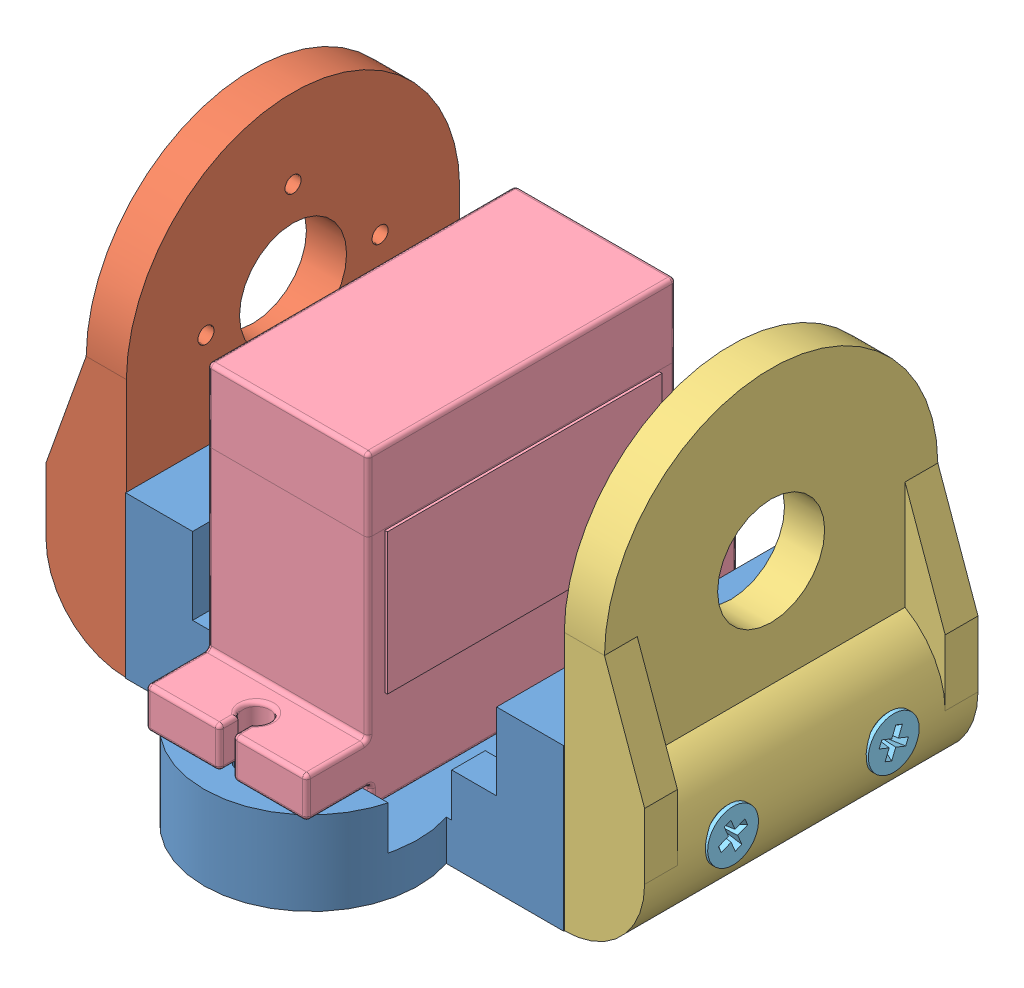
SolidWorks assembly Ensamblaje-Eslabon5, configuration Predeterminado. Lengths in mm.
Overall size (45.34 36.4 35.5).
8 component instances, 5 part files, 15 mates.
Components (placement in the parent):
- Eslabon5A-Servo-1: Eslabon5A-Servo [Predeterminado] at origin size (32.7 12 35.5)
- Eslabon5B-1: Eslabon5B [Predeterminado] at (-16.1231 15.0816 -5.7351) x (0 1 0) z (0 0 1) size (31.65 6 24.89)
- Eslabon5C-1: Eslabon5C [Predeterminado] at (16.5769 15.0816 -4.9919) x (0 1 0) z (0 0 -1) size (31.65 6 24.89)
- MG90S-Servo-1: MG90S-Servo [Default] at (0.2252 27.75 -0.1146) x (0 0 -1) z (-1 0 0) size (32.2 32.5 12.4)
- flat head screw_am-1: flat head screw_am [B18.6.7M - M2 x 0.4 x 13 Type I Cross Recessed FHMS --13S] at (-22.6064 6 -11.3635) x (1 0 0) z (0 0.146623 0.989192) size (13 3.8 3.8)
- flat head screw_am-2: flat head screw_am [B18.6.7M - M2 x 0.4 x 13 Type I Cross Recessed FHMS --13S] at (-22.6064 6 0.6365) size (13 3.8 3.8)
- flat head screw_am-3: flat head screw_am [B18.6.7M - M2 x 0.4 x 13 Type I Cross Recessed FHMS --13S] at (22.7349 6 0.6365) x (-1 0 0) z (0 -0.924225 -0.381849) size (13 3.8 3.8)
- flat head screw_am-4: flat head screw_am [B18.6.7M - M2 x 0.4 x 13 Type I Cross Recessed FHMS --13S] at (22.7349 6 -11.3635) x (-1 0 0) z (0 -0.374285 -0.927314) size (13 3.8 3.8)
Mates (geometry in assembly coordinates):
- Coincidente1: coincident: plane of Eslabon5A-Servo-1 through (0 6.25 0) normal (0 1 0); plane of MG90S-Servo-1 through (0.2252 6.25 -0.1146) normal (0 -1 0)
- Concéntrica1: concentric: cylinder of Eslabon5A-Servo-1 through (0.2252 3 -5.3646) axis (0 -1 0) radius 5.9982; cylinder of MG90S-Servo-1 through (0.2252 -1.25 -5.3646) axis (0 1 0) radius 5.75
- Paralelo2: parallel: plane of Eslabon5A-Servo-1 through (-11.1231 6.25 -11.3628) normal (1 0 0); plane of MG90S-Servo-1 through (-5.7748 9.25 11.3854) normal (-1 0 0)
- Coincidente2: coincident: plane of Eslabon5A-Servo-1 through (16.5769 3 -17.8635) normal (1 0 0); plane of Eslabon5C-1 through (16.5769 19.2008 -5.3641) normal (-1 0 0)
- Concéntrica4: concentric: cylinder of Eslabon5A-Servo-1 through (5.2269 6 0.6365) axis (1 0 0) radius 1; cylinder of Eslabon5C-1 through (19.5769 6 0.6365) axis (-1 0 0) radius 1
- Concéntrica5: concentric: cylinder of Eslabon5A-Servo-1 through (5.2269 6 -11.3635) axis (1 0 0) radius 1; cylinder of Eslabon5C-1 through (19.5769 6 -11.3635) axis (-1 0 0) radius 1
- Concéntrica6: concentric: cylinder of Eslabon5A-Servo-1 through (-4.7731 6 0.6365) axis (-1 0 0) radius 1; cylinder of Eslabon5B-1 through (-19.1231 6 0.6365) axis (1 0 0) radius 1
- Coincidente3: coincident: plane of Eslabon5A-Servo-1 through (-16.1231 3 -17.8635) normal (-1 0 0); plane of Eslabon5B-1 through (-16.1231 19.2008 -5.3628) normal (1 0 0)
- Concéntrica7: concentric: cylinder of Eslabon5A-Servo-1 through (-4.7731 6 -11.3635) axis (-1 0 0) radius 1; cylinder of Eslabon5B-1 through (-19.1231 6 -11.3635) axis (1 0 0) radius 1
- Concéntrica8: concentric: cylinder of Eslabon5B-1 through (-19.1231 6 0.6365) axis (1 0 0) radius 1; cone of flat head screw_am-2 through (-22.3064 6 0.6365) axis (1 0 0)
- Concéntrica9: concentric: cylinder of Eslabon5C-1 through (19.5769 6 -11.3635) axis (-1 0 0) radius 1; cone of flat head screw_am-4 through (22.4349 6 -11.3635) axis (-1 0 0)
- Coincidente4: coincident: axis of Eslabon5C-1 through (22.5769 6 0.6365) axis (-1 0 0); axis of flat head screw_am-3 through (9.8931 6 0.6365) axis (-1 0 0)
- Coincidente5: coincident: plane of flat head screw_am-3 through (22.7349 6 0.6365) normal (1 0 0); plane of flat head screw_am-4 through (22.7349 6 -11.3635) normal (1 0 0)
- Coincidente6: coincident: axis of Eslabon5B-1 through (-22.1231 6 -11.3635) axis (1 0 0); axis of flat head screw_am-1 through (-9.8413 6 -11.3635) axis (-1 0 0)
- Coincidente7: coincident: plane of flat head screw_am-1 through (-22.6064 6 -11.3635) normal (-1 0 0); plane of flat head screw_am-2 through (-22.6064 6 0.6365) normal (-1 0 0)
